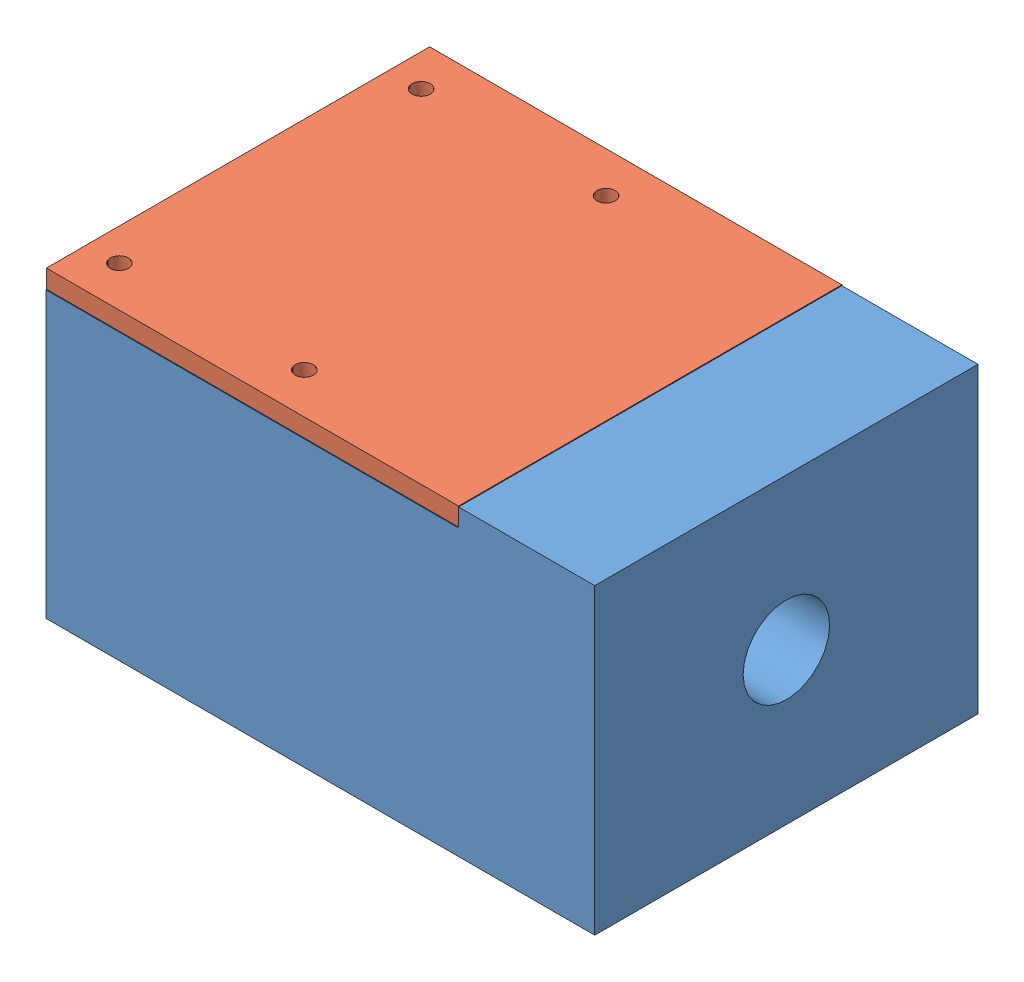
SolidWorks assembly Assembly detecteur, configuration Default. Lengths in mm.
Overall size (60.28 33.35 42.1).
2 component instances, 2 part files, 1 mates.
Components (placement in the parent):
- boite detecteur-2: boite detecteur [Default] at (-7.3733 12.7003 65.5736) size (60.28 33.26 42.1)
- capuchon detecteur-2: capuchon detecteur [Default] at (-7.3314 44.0496 65.5736) size (45.28 2 42.1)
Mates (geometry in assembly coordinates):
- Coincident2: coincident: plane of boite detecteur-2 through (-7.3733 12.7003 67.5736) normal (0 0 1); plane of capuchon detecteur-2 through (-7.3314 44.0496 67.5736) normal (0 0 1)
